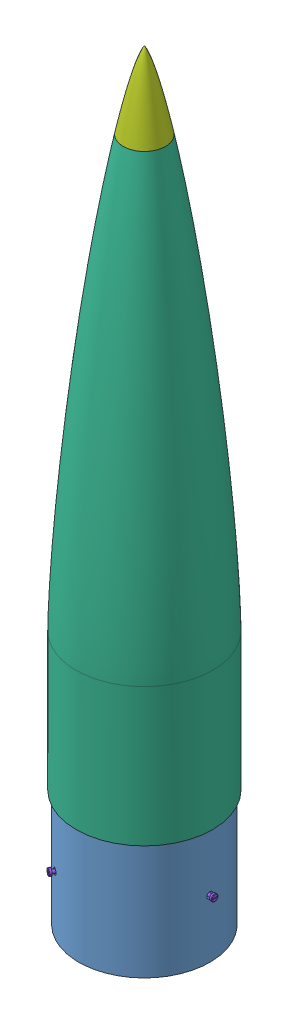
SolidWorks assembly S1B_Nose_Cone, configuration Default. Lengths in mm.
Overall size (80.74 442.25 79.45).
10 component instances, 8 part files, 24 mates.
Components (placement in the parent):
- S1B_Nose_Cone_Shoulder_Tube-1: S1B_Nose_Cone_Shoulder_Tube [Default] at origin size (76.28 147.82 76.28)
- S1B_Nose_Cone_Bulkhead-1: S1B_Nose_Cone_Bulkhead [Default] at (0 141.4653 0) size (73.03 6.35 73.03)
- S1B_Nose_Cone_Recovery_Eyebolt_3014T45_Steel Eyebolt with Shoulder - for Lifting-1: S1B_Nose_Cone_Recovery_Eyebolt_3014T45_Steel Eyebolt with Shoulder - for Lifting [3014T45] at (0 117.6528 0) x (-1 0 0) z (0 0 1) size (30.16 64.29 14.29)
- S1B_Nose_Cone_Recovery_Nut_95462A029_Medium-Strength Steel Hex Nut-1: S1B_Nose_Cone_Recovery_Nut_95462A029_Medium-Strength Steel Hex Nut [95462A029] at (0 151.6856 0) x (1 0 0) z (0 1 0) size (11.11 12.83 5.56)
- S1B_Nose_Cone_Recovery_Washer_90107A029_316 Stainless Steel Washer-1: S1B_Nose_Cone_Recovery_Washer_90107A029_316 Stainless Steel Washer [90107A029] at (0 147.8153 0) x (-1 0 0) z (0 0 -1) size (15.88 1.09 15.88)
- S1B_Nose_Cone-1: S1B_Nose_Cone [Default] at (0 442.2522 0) x (0 -1 0) z (0 0 -1) size (330.2 79.45 79.45)
- S1B_Nose_Cone_Tip-1: S1B_Nose_Cone_Tip [Default] at (0 442.2521 0) x (0 -1 0) z (0 0 1) size (44.45 24.48 24.48)
- S1B_Shear_Pin-1: S1B_Shear_Pin [Default] at (39.7256 33.8074 0) x (0 -1 0) z (-1 0 0) size (3.81 3.83 10.38)
- S1B_Shear_Pin-2: S1B_Shear_Pin [Default] at (-19.8628 33.8074 -34.4034) x (0 -1 0) z (0.5 0 0.866025) size (3.81 3.83 10.38)
- S1B_Shear_Pin-3: S1B_Shear_Pin [Default] at (-19.8628 33.8074 34.4034) x (0 -1 0) z (0.5 0 -0.866025) size (3.81 3.83 10.38)
Mates (geometry in assembly coordinates):
- Coincident1: coincident anti-aligned: line of S1B_Nose_Cone_Shoulder_Tube-1 through (162.4711 0 155.0861) axis (0 0 -1)
- Coincident2: coincident aligned: plane of S1B_Nose_Cone_Shoulder_Tube-1 through (0 0 0) normal (0 1 0)
- Coincident3: coincident aligned: plane of S1B_Nose_Cone_Shoulder_Tube-1 through (0 0 0) normal (0 0 1)
- Coincident4: coincident aligned: line of S1A_Nose_Cone_Bulkhead-1 through (6.985 0 141.1478) axis (0 0 1)
- Parallel1: parallel aligned: plane of S1A_Nose_Cone_Bulkhead-1 through (0 141.4653 0) normal (0 0 1)
- Distance1: distance = 0 mm aligned: plane of S1A_Nose_Cone_Bulkhead-1 through (0 147.8153 0) normal (0 1 0); plane of S1B_Nose_Cone_Shoulder_Tube-1 through (0 147.8153 0) normal (0 1 0)
- Coincident5: coincident anti-aligned: line of S1A_Nose_Cone_Recovery_Eyebolt_3014T45_Steel Eyebolt with Shoulder - for Lifting-1 through (70.7231 0 170.08) axis (0 0 -1)
- Parallel2: parallel aligned: plane of S1A_Nose_Cone_Recovery_Eyebolt_3014T45_Steel Eyebolt with Shoulder - for Lifting-1 through (0 117.6528 0) normal (0 0 1)
- Coincident6: coincident anti-aligned: plane of S1A_Nose_Cone_Bulkhead-1 through (0 141.4653 0) normal (0 -1 0); plane of S1A_Nose_Cone_Recovery_Eyebolt_3014T45_Steel Eyebolt with Shoulder - for Lifting-1 through (6.4492 141.4653 0) normal (0 1 0)
- Coincident7: coincident anti-aligned: line of S1A_Nose_Cone_Recovery_Nut_95462A029_Medium-Strength Steel Hex Nut-1 through (6.1119 0 154.7416) axis (0 0 -1)
- Parallel3: parallel anti-aligned: plane of S1A_Nose_Cone_Recovery_Nut_95462A029_Medium-Strength Steel Hex Nut-1 through (0 151.6856 0) normal (0 0 -1)
- Coincident9: coincident aligned: line of S1A_Nose_Cone_Recovery_Washer_90107A029_316 Stainless Steel Washer-1 through (1.2014 0 147.7607) axis (0 0 1)
- Coincident10: coincident anti-aligned: plane of S1A_Nose_Cone_Bulkhead-1 through (0 147.8153 0) normal (0 1 0); plane of S1A_Nose_Cone_Recovery_Washer_90107A029_316 Stainless Steel Washer-1 through (0 147.8153 0) normal (0 -1 0)
- Parallel4: parallel anti-aligned: plane of S1A_Nose_Cone_Recovery_Washer_90107A029_316 Stainless Steel Washer-1 through (0 147.8153 0) normal (0 0 -1)
- Coincident11: coincident anti-aligned: plane of S1A_Nose_Cone_Recovery_Nut_95462A029_Medium-Strength Steel Hex Nut-1 through (-5.5563 148.9075 -3.2079) normal (0 -1 0); plane of S1A_Nose_Cone_Recovery_Washer_90107A029_316 Stainless Steel Washer-1 through (0 148.9075 0) normal (0 1 0)
- Parallel7: parallel aligned: plane of S1A_Nose_Cone_Tip-1 through (0 442.2521 0) normal (0 0 1)
- Coincident17: coincident aligned: line of S1A_Nose_Cone_Tip-1 through (48.895 0 395.5796) axis (0 0 1)
- Coincident18: coincident anti-aligned: line of S1B_Nose_Cone-1 through (0 461.3022 0) axis (0 -1 0)
- Parallel8: parallel anti-aligned: plane of S1B_Nose_Cone-1 through (0 442.2522 0) normal (0 0 -1)
- Coincident19: coincident anti-aligned: plane of S1B_Nose_Cone_Shoulder_Tube-1 through (0 147.8153 0) normal (0 1 0); plane of S1B_Nose_Cone-1 through (0 147.8153 0) normal (0 -1 0)
- Coincident20: coincident aligned: plane of S1B_Nose_Cone-1 through (0 397.8021 0) normal (0 -1 0); plane of S1A_Nose_Cone_Tip-1 through (0 397.8021 0) normal (0 -1 0)
- Concentric1: concentric anti-aligned: cylinder of S1B_Nose_Cone_Shoulder_Tube-1 through (-38.1391 33.8074 0) axis (1 0 0) radius 1.7859; cylinder of S1A_Shear_Pin-1 through (-15.2744 33.8074 0) axis (-1 0 0) radius 0.9906
- Coincident21: coincident anti-aligned: plane of S1A_Shear_Pin-1 through (39.7256 33.8074 1.905) normal (-1 0 0)
- Parallel9: parallel aligned: plane of S1A_Shear_Pin-1 through (40.7416 33.6804 0) normal (0 1 0)
